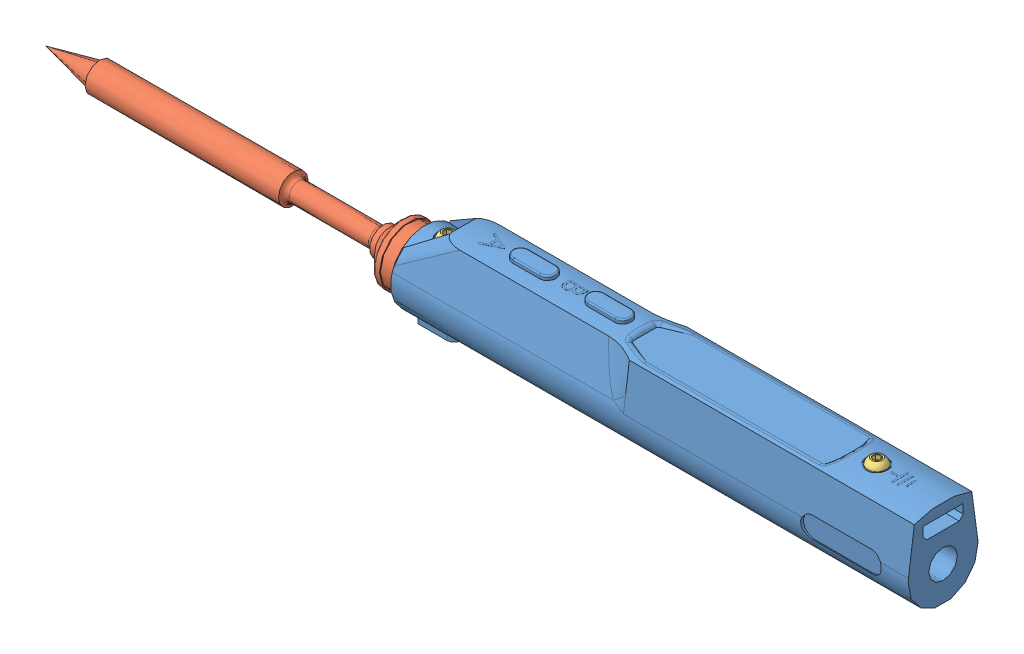
SolidWorks assembly TS100 Soldering Iron ASSY, configuration Default. Lengths in mm.
Overall size (166.85 20.49 13.61).
5 component instances, 3 part files, 0 mates.
Components (placement in the parent):
- TS100 Body-1: TS100 Body [默认] at origin size (97.33 18.88 13.61)
- TS100 Tips_TS-B2-1: TS100 Tips_TS-B2 [默认] at (-97 0 0) size (103.35 10.95 10.95)
- 18-8 SS BH SH Cap Screw M2x4mm - 92095A451_92095A451-1: 18-8 SS BH SH Cap Screw M2x4mm - 92095A451_92095A451 [默认] at (-92.1 7.4 0) x (1 0 0) z (0 1 0) size (3.51 3.53 5.61)
- 18-8 SS BH SH Cap Screw M2x4mm - 92095A451_92095A451-2: 18-8 SS BH SH Cap Screw M2x4mm - 92095A451_92095A451 [默认] at (-12.3 11.05 0) x (1 0 0) z (0 1 0) size (3.51 3.53 5.61)
- 18-8 SS BH SH Cap Screw M2x4mm - 92095A451_92095A451-3: 18-8 SS BH SH Cap Screw M2x4mm - 92095A451_92095A451 [默认] at (-91.7 -8.8 0) x (-1 0 0) z (0 -1 0) size (3.51 3.53 5.61)
